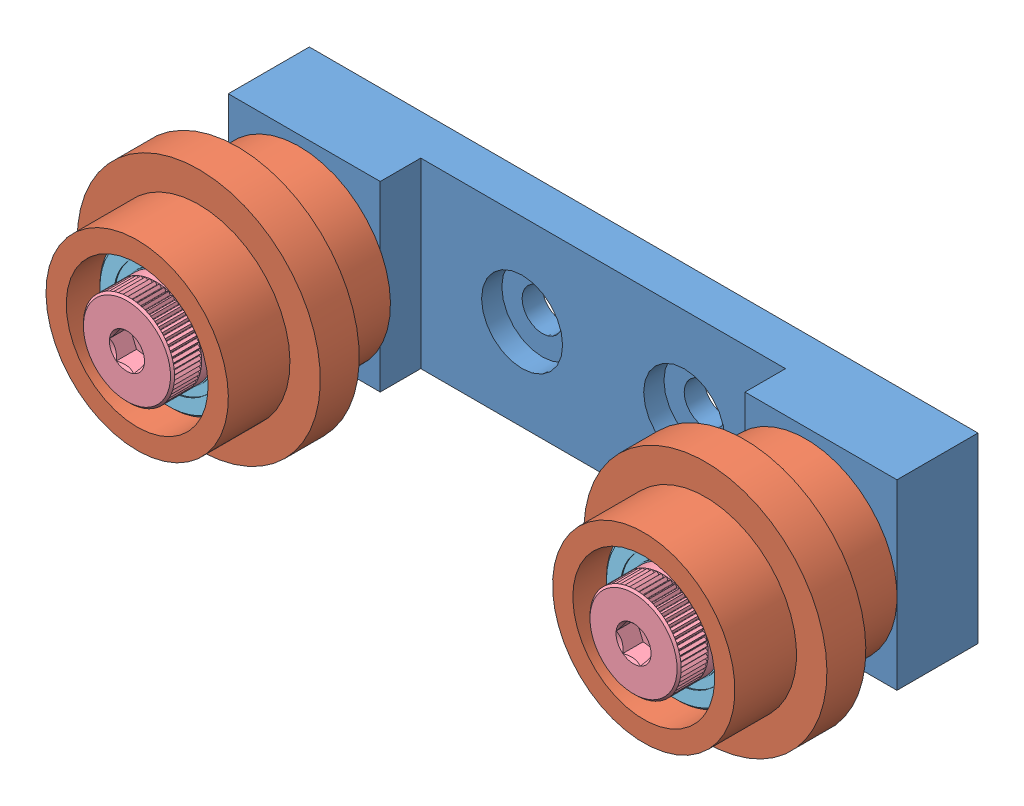
SolidWorks assembly 2018-307-AA, configuration Default. Lengths in mm.
Overall size (130.71 51.83 41.78).
11 component instances, 5 part files, 20 mates.
Components (placement in the parent):
- 2018-307-D0011-1: 2018-307-D0011 [Default] at origin size (104.77 28.57 12.7)
- 2018-310-D002-1: 2018-310-D002 [Default] at (39.6875 14.2875 14.2748) x (0.873514 0.486798 0) z (0 0 -1) size (38.1 38.1 25.4)
- 2018-310-D002-2: 2018-310-D002 [Default] at (-39.6875 14.2875 14.2748) x (0.901311 0.433173 0) z (0 0 -1) size (38.1 38.1 25.4)
- 375x875WasherBrassMC92916A405-1: 375x875WasherBrassMC92916A405 [Default] at (39.6875 14.2875 14.2748) x (0.923728 0.383049 0) z (-0.383049 0.923728 0) size (22.23 1.57 22.23)
- 375x875WasherBrassMC92916A405-2: 375x875WasherBrassMC92916A405 [Default] at (-39.6875 14.2875 12.7) x (0.923728 0.383049 0) z (0.383049 -0.923728 0) size (22.23 1.57 22.23)
- 375x1000ShoulderBoltMC91259A623-1: 375x1000ShoulderBoltMC91259A623 [91259A623] at (-39.6875 14.2875 34.925) x (0.923728 0.383049 0) z (0.383049 -0.923728 0) size (14.29 41.78 14.29)
- 375x1000ShoulderBoltMC91259A623-2: 375x1000ShoulderBoltMC91259A623 [91259A623] at (39.6875 14.2875 34.925) x (0.923728 0.383049 0) z (0.383049 -0.923728 0) size (14.29 41.78 14.29)
- 375x875BallBearingMC60355K450-1: 375x875BallBearingMC60355K450 [60355K45] at (39.6875 14.2875 17.8149) x (0.923728 0.383049 0) z (0 0 -1) size (22.23 22.23 7.14)
- 375x875BallBearingMC60355K450-2: 375x875BallBearingMC60355K450 [60355K45] at (-39.6875 14.2875 31.1817) x (0.923728 0.383049 0) z (0 0 -1) size (22.23 22.23 7.14)
- 375x875BallBearingMC60355K450-3: 375x875BallBearingMC60355K450 [60355K45] at (-39.6875 14.2875 17.8149) x (0.923728 0.383049 0) z (0 0 -1) size (22.23 22.23 7.14)
- 375x875BallBearingMC60355K450-4: 375x875BallBearingMC60355K450 [60355K45] at (39.6875 14.2875 31.1817) x (0.923728 0.383049 0) z (0 0 -1) size (22.23 22.23 7.14)
Mates (geometry in assembly coordinates):
- Coincident3: coincident anti-aligned: plane of 2018-307-D0011-1 through (52.3875 28.575 12.7) normal (0 0 1); plane of 375x875WasherBrassMC92916A405-1 through (39.6875 14.2875 12.7) normal (0 0 -1)
- Coincident4: coincident anti-aligned: plane of 2018-307-D0011-1 through (-28.575 28.575 12.7) normal (0 0 1); plane of 375x875WasherBrassMC92916A405-2 through (-39.6875 14.2875 12.7) normal (0 0 -1)
- Coincident5: coincident anti-aligned: plane of 2018-310-D002-2 through (-39.6875 14.2875 14.2748) normal (0 0 -1); plane of 375x875WasherBrassMC92916A405-2 through (-39.6875 14.2875 14.2748) normal (0 0 1)
- Coincident6: coincident anti-aligned: plane of 2018-310-D002-1 through (39.6875 14.2875 14.2748) normal (0 0 -1); plane of 375x875WasherBrassMC92916A405-1 through (39.6875 14.2875 14.2748) normal (0 0 1)
- Concentric1: concentric anti-aligned: cylinder of 2018-307-D0011-1 through (39.6875 14.2875 12.7) axis (0 0 1) radius 3.2639; cylinder of 375x1000ShoulderBoltMC91259A623-2 through (39.6875 14.2875 34.925) axis (0 0 -1) radius 4.7625
- Concentric2: concentric anti-aligned: cylinder of 2018-307-D0011-1 through (-39.6875 14.2875 12.7) axis (0 0 1) radius 3.2639; cylinder of 375x1000ShoulderBoltMC91259A623-1 through (-39.6875 14.2875 34.925) axis (0 0 -1) radius 4.7625
- Coincident7: coincident anti-aligned: plane of 2018-307-D0011-1 through (-28.575 28.575 12.7) normal (0 0 1); plane of 375x1000ShoulderBoltMC91259A623-1 through (-39.6875 14.2875 12.7) normal (0 0 -1)
- Coincident8: coincident anti-aligned: plane of 2018-307-D0011-1 through (52.3875 28.575 12.7) normal (0 0 1); plane of 375x1000ShoulderBoltMC91259A623-2 through (39.6875 14.2875 12.7) normal (0 0 -1)
- Concentric3: concentric aligned: cylinder of 2018-310-D002-2 through (-39.6875 14.2875 14.2748) axis (0 0 -1) radius 5.0419; cylinder of 375x1000ShoulderBoltMC91259A623-1 through (-39.6875 14.2875 34.925) axis (0 0 -1) radius 4.7625
- Concentric4: concentric aligned: cylinder of 2018-310-D002-1 through (39.6875 14.2875 14.2748) axis (0 0 -1) radius 5.0419; cylinder of 375x1000ShoulderBoltMC91259A623-2 through (39.6875 14.2875 34.925) axis (0 0 -1) radius 4.7625
- Concentric5: concentric anti-aligned: cylinder of 375x875WasherBrassMC92916A405-1 through (39.6875 14.2875 12.7) axis (0 0 1) radius 4.9784; cylinder of 375x1000ShoulderBoltMC91259A623-2 through (39.6875 14.2875 34.925) axis (0 0 -1) radius 4.7625
- Concentric6: concentric aligned: cylinder of 375x875WasherBrassMC92916A405-2 through (-39.6875 14.2875 14.2748) axis (0 0 -1) radius 4.9784; cylinder of 375x1000ShoulderBoltMC91259A623-1 through (-39.6875 14.2875 34.925) axis (0 0 -1) radius 4.7625
- Concentric7: concentric aligned: cylinder of 375x1000ShoulderBoltMC91259A623-1 through (-39.6875 14.2875 34.925) axis (0 0 -1) radius 4.7625; cylinder of 375x875BallBearingMC60355K450-3 through (-39.6875 14.2875 28.5305) axis (0 0 1) radius 4.7625
- Concentric8: concentric aligned: cylinder of 375x1000ShoulderBoltMC91259A623-1 through (-39.6875 14.2875 34.925) axis (0 0 -1) radius 4.7625; cylinder of 375x875BallBearingMC60355K450-2 through (-39.6875 14.2875 27.6098) axis (0 0 -1) radius 4.7625
- Concentric9: concentric aligned: cylinder of 375x1000ShoulderBoltMC91259A623-2 through (39.6875 14.2875 34.925) axis (0 0 -1) radius 4.7625; cylinder of 375x875BallBearingMC60355K450-1 through (39.6875 14.2875 14.2431) axis (0 0 -1) radius 4.7625
- Concentric10: concentric aligned: cylinder of 375x1000ShoulderBoltMC91259A623-2 through (39.6875 14.2875 34.925) axis (0 0 -1) radius 4.7625; cylinder of 375x875BallBearingMC60355K450-4 through (39.6875 14.2875 27.6098) axis (0 0 -1) radius 4.7625
- Coincident9: coincident anti-aligned: plane of 2018-310-D002-1 through (39.6875 14.2875 27.6098) normal (0 0 1); plane of 375x875BallBearingMC60355K450-4 through (43.8073 4.3525 27.6098) normal (0 0 -1)
- Coincident10: coincident anti-aligned: plane of 2018-310-D002-1 through (39.6875 14.2875 21.3868) normal (0 0 -1); plane of 375x875BallBearingMC60355K450-1 through (43.8073 4.3525 21.3868) normal (0 0 1)
- Coincident12: coincident anti-aligned: plane of 2018-310-D002-2 through (-39.6875 14.2875 21.3868) normal (0 0 -1); plane of 375x875BallBearingMC60355K450-3 through (-35.5677 4.3525 21.3868) normal (0 0 1)
- Coincident13: coincident anti-aligned: plane of 2018-310-D002-2 through (-39.6875 14.2875 27.6098) normal (0 0 1); plane of 375x875BallBearingMC60355K450-2 through (-35.5677 4.3525 27.6098) normal (0 0 -1)
